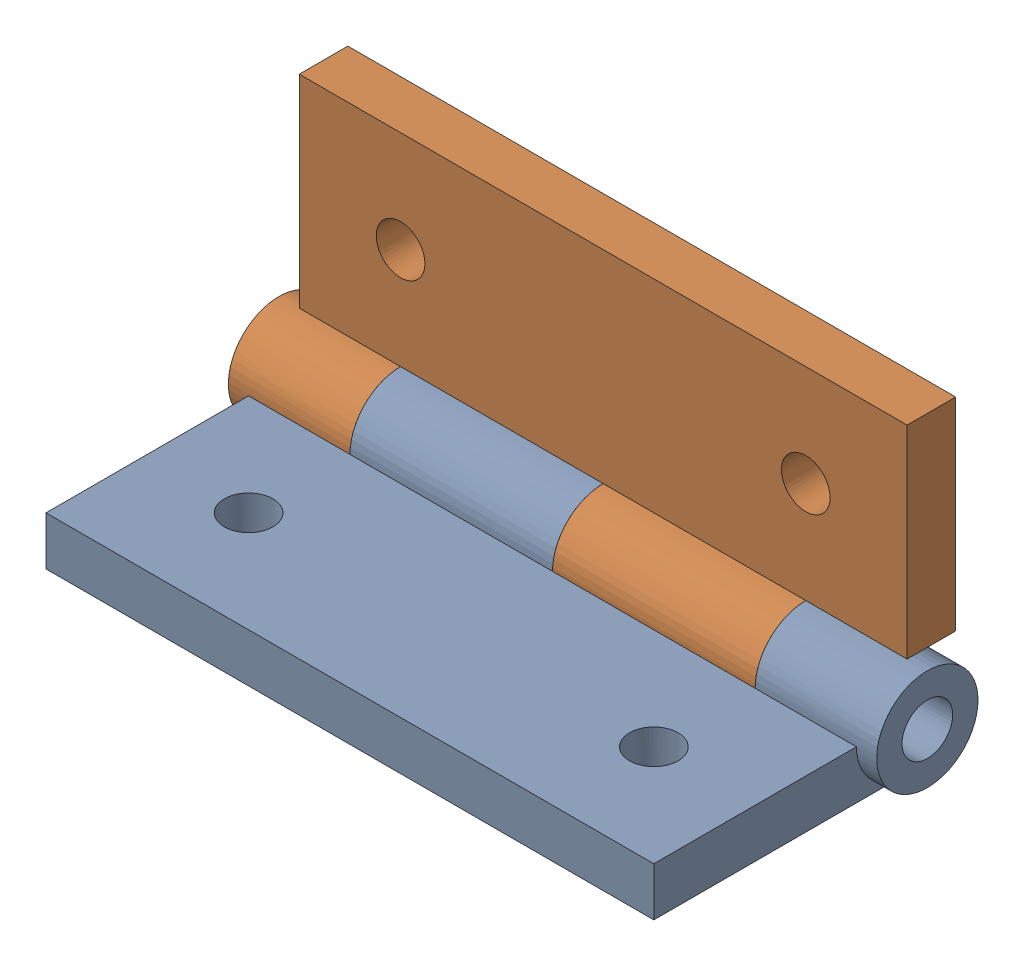
SolidWorks assembly Pack_and_go_Electroporation BoxHinge Full 2, configuration Default. Lengths in mm.
Overall size (40.64 19.05 19.05).
2 component instances, 1 part files, 2 mates.
Components (placement in the parent):
- Pack_and_go_Electroporation BoxHinge-1: Pack_and_go_Electroporation BoxHinge [Default] at (-53.6638 3.3805 25.2027) size (39.37 6.35 19.05)
- Pack_and_go_Electroporation BoxHinge-2: Pack_and_go_Electroporation BoxHinge [Default] at (-53.6638 14.3661 14.2173) x (-1 0 0) z (0 1 0.000022) size (39.37 6.35 19.05)
Mates (geometry in assembly coordinates):
- Concentric1: concentric anti-aligned: circle of Pack_and_go_Electroporation BoxHinge-1; circle of Pack_and_go_Electroporation BoxHinge-2
- Coincident2: coincident anti-aligned: plane of Pack_and_go_Electroporation BoxHinge-1 through (-66.3638 9.6035 14.0902) normal (-1 0 0); plane of Pack_and_go_Electroporation BoxHinge-2 through (-66.3638 3.2534 20.4401) normal (1 0 0)
